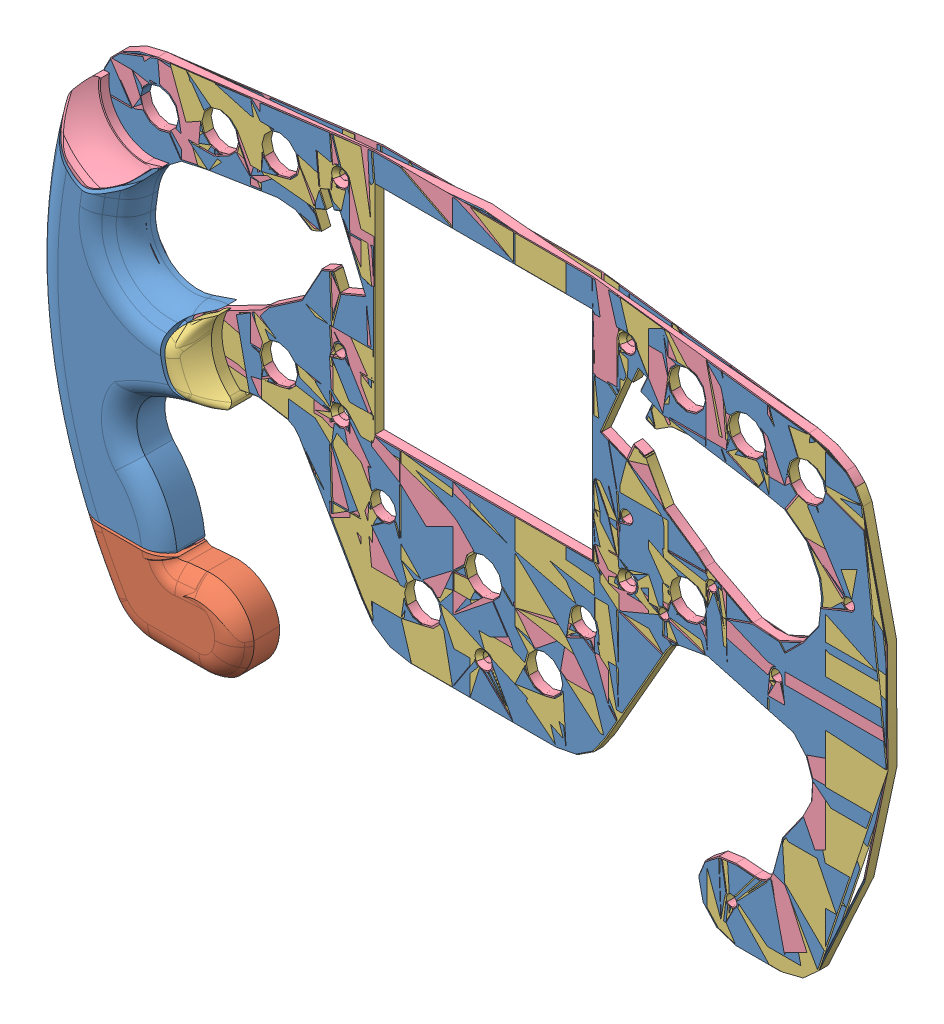
SolidWorks assembly left grip assembly, configuration Default. Lengths in mm.
Overall size (68.83 150.25 15.01).
4 component instances, 4 part files, 12 mates.
Components (placement in the parent):
- left grip no ends or edges-1: left grip no ends or edges [Default] at (82.6904 40.4146 11.7802) size (272.22 167.67 14.17)
- bottom end-1: bottom end [Default] at (82.6904 40.4146 11.7802) size (55.53 45.36 15)
- middle end-1: middle end [Default] at (83.1819 40.5061 11.7802) size (236.96 167.67 14.21)
- top end with extended screw hold-1: top end with extended screw hold [Default] at (82.8 40.9025 11.7802) size (267.09 167.67 14.23)
Mates (geometry in assembly coordinates):
- Coincident1: coincident aligned: plane of left grip no ends or edges-1 through (82.6904 40.4146 11.7802) normal (0 0 -1); plane of bottom end-1 through (82.6904 40.4146 11.7802) normal (0 0 -1)
- Coincident2: coincident aligned: plane of left grip no ends or edges-1 through (82.6904 40.4146 11.7802) normal (0 0 -1); plane of top end-1 through (82.6904 40.4146 11.7802) normal (0 0 -1)
- Parallel1: parallel aligned: line of left grip no ends or edges-1 through (-16.1425 -18.1674 25.2802) axis (-1 0 0); line of bottom end-1 through (-16.0263 -19.0674 25.2802) axis (-1 0 0)
- Concentric3: concentric aligned: cylinder of left grip no ends or edges-1 through (116.1065 46.6634 26.7802) axis (0 0 -1) radius 169.0986; cylinder of bottom end-1 through (116.1065 46.6634 26.7802) axis (0 0 -1) radius 169.0986
- Concentric5: concentric aligned: cylinder of left grip no ends or edges-1 through (-16.4419 76.0793 26.7802) axis (0 0 -1) radius 33.4055; cylinder of top end-1 through (-16.4419 76.0793 26.7802) axis (0 0 -1) radius 33.4055
- Concentric6: concentric aligned: cylinder of left grip no ends or edges-1 through (116.1065 46.6634 26.7802) axis (0 0 -1) radius 167.5986; cylinder of top end-1 through (116.1065 46.6634 26.7802) axis (0 0 -1) radius 167.5986
- Coincident3: coincident: plane of left grip no ends or edges-1 through (82.6904 40.4146 11.7802) normal (0 0 -1); plane of middle end-1 through (83.1911 39.0411 11.7802) normal (0 0 -1)
- Concentric8: concentric aligned: cylinder of left grip no ends or edges-1 through (-35.1709 77.1534 25.9478) axis (0 0 -1) radius 1.75; cylinder of top end with extended screw hold-1 through (-35.1709 77.1534 21.2802) axis (0 0 -1) radius 1.55
- Coincident4: coincident anti-aligned: plane of left grip no ends or edges-1 through (-37.3165 80.1979 18.7802) normal (0 0 1); plane of top end with extended screw hold-1 through (82.8 40.9025 18.7802) normal (0 0 -1)
- Parallel5: parallel aligned: plane of left grip no ends or edges-1 through (85.4319 52.6152 11.7802) normal (0.219242 0.975671 0); plane of top end with extended screw hold-1 through (-31.8196 79.4751 21.0302) normal (0.219242 0.975671 0)
- Concentric14: concentric: cylinder of left grip no ends or edges-1 through (-6.6264 39.2121 21.7802) axis (0 0 -1) radius 1.75; cylinder of middle end-1 through (-6.6264 39.2121 25.9883) axis (0 0 -1) radius 1.55
- Parallel7: parallel aligned: plane of left grip no ends or edges-1 through (-1.3982 24.7746 11.7802) normal (0.983139 0.182858 0); plane of middle end-1 through (-4.3408 43.3296 25.9883) normal (0.983139 0.182858 0)
